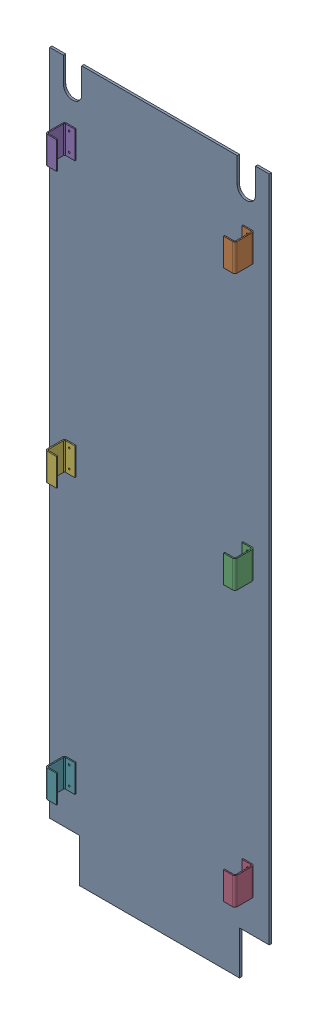
SolidWorks assembly GE-16071_ASM, configuration Default. Lengths in mm.
Overall size (609.6 1974.85 60.33).
7 component instances, 2 part files, 0 mates.
Components (placement in the parent):
- GE-16072-1: GE-16072 [Default] at origin size (609.6 1974.85 6.35)
- GE-16070-1: GE-16070 [Default] at (263.525 752.475 6.35) x (0 0 -1) z (1 0 0) size (53.98 76.2 31.75)
- GE-16070-2: GE-16070 [Default] at (263.525 -9.525 6.35) x (0 0 -1) z (1 0 0) size (53.98 76.2 31.75)
- GE-16070-3: GE-16070 [Default] at (263.525 -771.525 6.35) x (0 0 -1) z (1 0 0) size (53.98 76.2 31.75)
- GE-16070-4: GE-16070 [Default] at (-263.525 828.675 6.35) x (0 0 -1) z (-1 0 0) size (53.98 76.2 31.75)
- GE-16070-5: GE-16070 [Default] at (-263.525 66.675 6.35) x (0 0 -1) z (-1 0 0) size (53.98 76.2 31.75)
- GE-16070-6: GE-16070 [Default] at (-263.525 -695.325 6.35) x (0 0 -1) z (-1 0 0) size (53.98 76.2 31.75)
